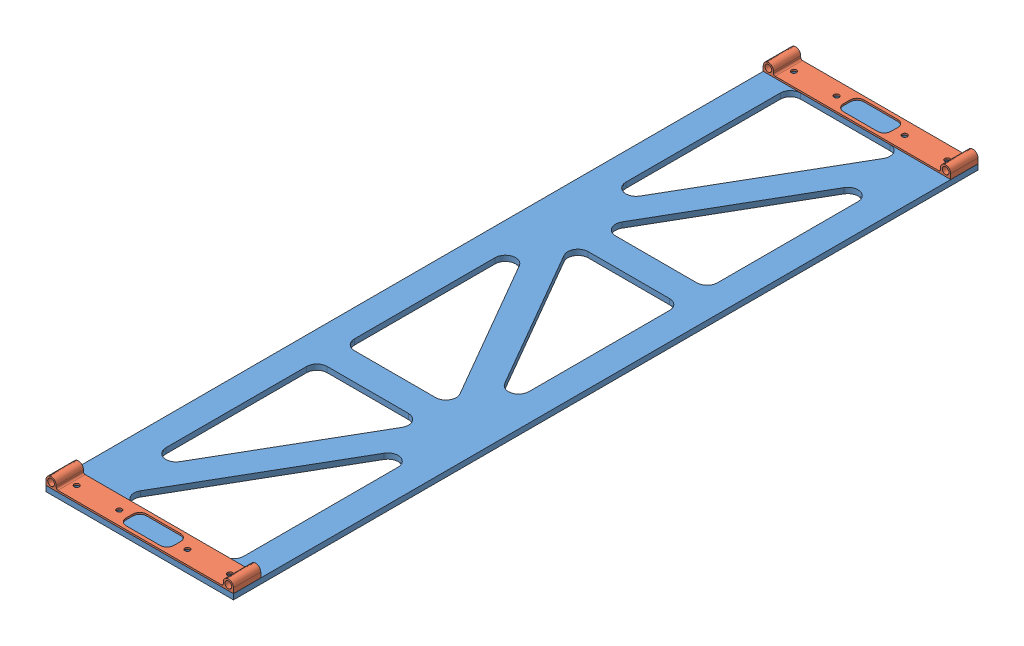
SolidWorks assembly Array Panel Support, configuration Default. Lengths in mm.
Overall size (349.25 29.21 1386.93).
3 component instances, 2 part files, 13 mates.
Components (placement in the parent):
- Solar Support-1: Solar Support [Default] at (132.2414 -50.7179 14.6661) x (0 0 1) z (-1 0 0) size (1386.93 10.16 349.25)
- Pin Attatchment Bracket-5: Pin Attatchment Bracket [Default] at (141.7664 -31.0329 14.6661) size (349.25 19.05 50.8)
- Pin Attatchment Bracket-6: Pin Attatchment Bracket [Default] at (141.7664 -31.0329 1350.795) size (349.25 19.05 50.8)
Mates (geometry in assembly coordinates):
- Coincident22: coincident anti-aligned: plane of Solar Support-1 through (132.2414 -40.5579 14.6661) normal (0 1 0); plane of Pin Attatchment Bracket-5 through (141.7664 -40.5579 65.4661) normal (0 -1 0)
- Coincident23: coincident aligned: line of Solar Support-1 through (132.2414 -40.5579 14.6661) axis (1 0 0); line of Pin Attatchment Bracket-5 through (132.2414 -40.5579 14.6661) axis (1 0 0)
- Coincident24: coincident aligned: plane of Solar Support-1 through (132.2414 -40.5579 14.6661) normal (-1 0 0); plane of Pin Attatchment Bracket-5 through (132.2414 -31.0329 65.4661) normal (-1 0 0)
- Coincident25: coincident anti-aligned: plane of Solar Support-1 through (132.2414 -40.5579 14.6661) normal (0 1 0); plane of Pin Attatchment Bracket-6 through (141.7664 -40.5579 1401.595) normal (0 -1 0)
- Coincident26: coincident aligned: plane of Solar Support-1 through (132.2414 -40.5579 1401.595) normal (0 0 1); plane of Pin Attatchment Bracket-6 through (141.7664 -31.0329 1401.595) normal (0 0 1)
- Coincident27: coincident aligned: plane of Solar Support-1 through (132.2414 -40.5579 14.6661) normal (-1 0 0); plane of Pin Attatchment Bracket-6 through (132.2414 -31.0329 1401.595) normal (-1 0 0)
- Coincident28: coincident anti-aligned: plane of Solar Support-1 through (132.2414 -40.5579 14.6661) normal (0 1 0); plane of Pin Attatchment Bracket-8 through (469.5852 -40.5579 1350.795) normal (0 -1 0)
- Parallel2: parallel aligned: plane of Solar Support-1 through (481.4914 -40.5579 14.6661) normal (1 0 0); plane of Pin Attatchment Bracket-8 through (476.7289 -33.4141 1350.795) normal (1 0 0)
- Coincident32: coincident aligned: plane of Solar Support-1 through (132.2414 -40.5579 1401.595) normal (0 0 1); plane of Pin Attatchment Bracket-8 through (469.5852 -33.4141 1401.595) normal (0 0 1)
- Distance5: distance = 330.2 mm: cylinder of Pin Attatchment Bracket-8 through (469.5852 -33.4141 1350.795) axis (0 0 1) radius 3.9688; cylinder of Pin Attatchment Bracket-6 through (141.7664 -31.0329 1401.595) axis (0 0 -1) radius 6.35
- Coincident33: coincident anti-aligned: plane of Solar Support-1 through (132.2414 -40.5579 14.6661) normal (0 1 0); plane of Pin Attatchment Bracket-7 through (469.5852 -40.5579 14.6661) normal (0 -1 0)
- Coincident34: coincident aligned: plane of Solar Support-1 through (132.2414 -40.5579 14.6661) normal (0 0 -1); plane of Pin Attatchment Bracket-7 through (469.5852 -33.4141 14.6661) normal (0 0 -1)
- Distance6: distance = 330.2 mm: cylinder of Pin Attatchment Bracket-7 through (469.5852 -33.4141 14.6661) axis (0 0 1) radius 3.9688; cylinder of Pin Attatchment Bracket-5 through (141.7664 -31.0329 65.4661) axis (0 0 -1) radius 6.35
